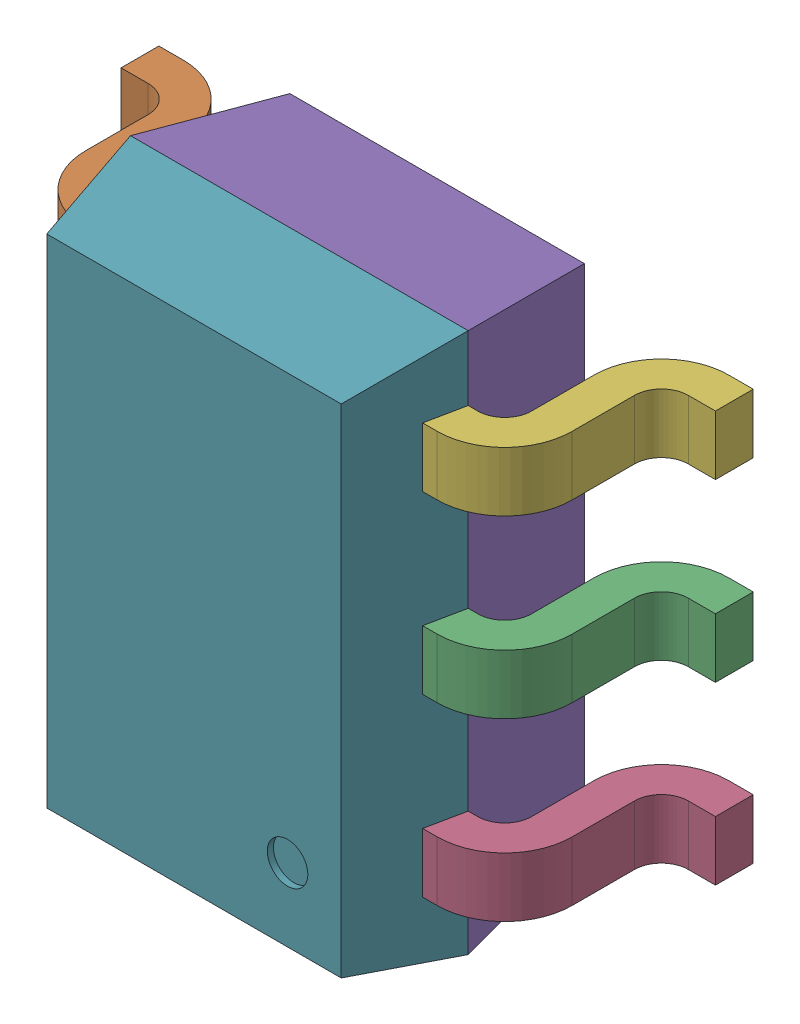
SolidWorks assembly U20.step, configuration Default. Lengths in mm.
Overall size (2.2 2 0.97).
8 component instances, 7 part files, 0 mates.
Components (placement in the parent):
- User Library-SC70-5.step-1: User Library-SC70-5.step [Default] at (26.416 -17.1451 0.4826) x (0 1 0) z (1 0 0) size (2 0.97 2.2)
  - User Library-SC70-5_6_1.step-1: User Library-SC70-5_6_1.step [Default] at origin size (0.22 0.72 0.56)
  - User Library-SC70-5_5_1.step-1: User Library-SC70-5_5_1.step [Default] at origin size (0.22 0.72 0.56)
  - User Library-SC70-5_2_1.step-1: User Library-SC70-5_2_1.step [Default] at origin size (0.22 0.72 0.56)
  - User Library-SC70-5_4_1.step-1: User Library-SC70-5_4_1.step [Default] at origin size (0.22 0.72 0.56)
  - User Library-SC70-5_1_1.step-1: User Library-SC70-5_1_1.step [Default] at origin size (2 0.51 1.25)
  - User Library-SC70-5_3_1.step-1: User Library-SC70-5_3_1.step [Default] at origin size (0.22 0.72 0.56)
  - User Library-SC70-5_7_1.step-1: User Library-SC70-5_7_1.step [Default] at origin size (2 0.39 1.25)
